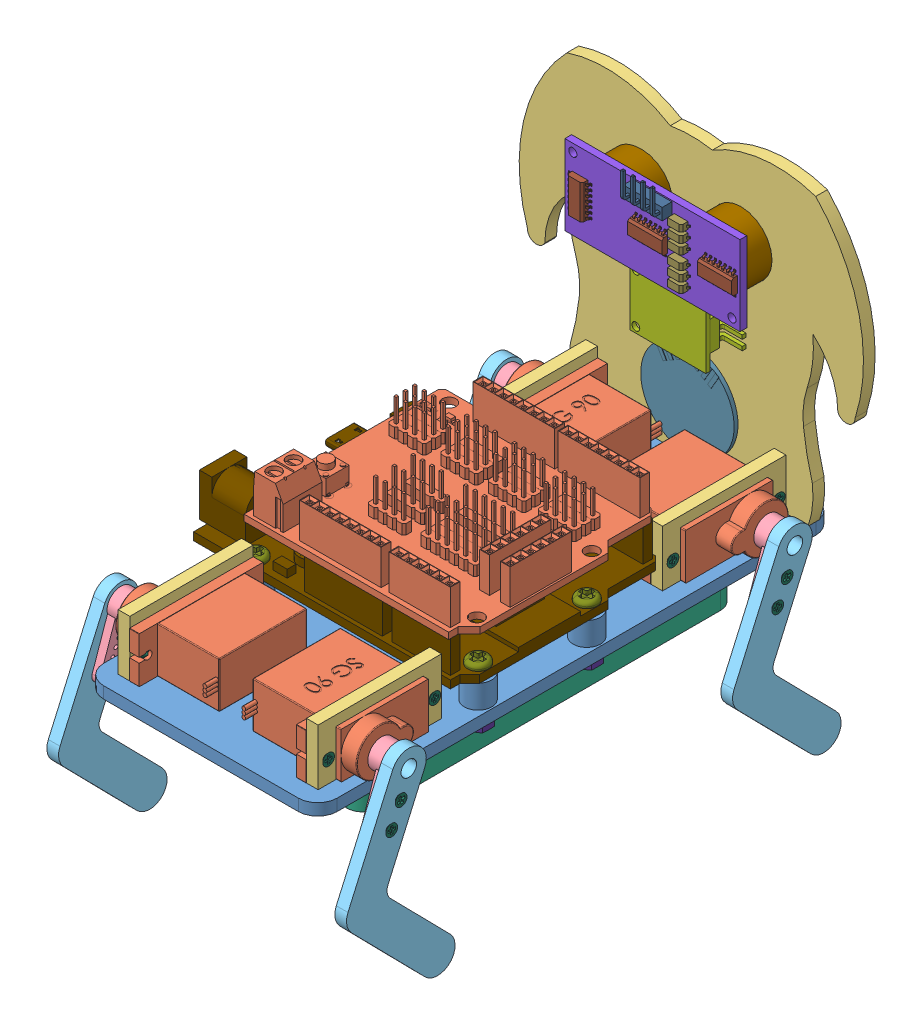
SolidWorks assembly nelo, configuration Default. Lengths in mm.
Overall size (88.48 121.83 157.12).
70 component instances, 21 part files, 115 mates.
Components (placement in the parent):
- Base-1: Base [Default] at (-3.0224 29.2064 91.2375) size (60 3 133)
- sg90-1: sg90 [Default] at (22.6776 44.0064 -3.7625) x (0 0 1) z (0 -1 0) size (31.9 29.9 11.8)
- sg90-2: sg90 [Default] at (31.2776 44.0064 107.2375) x (0 0 -1) z (0 -1 0) size (31.9 29.9 11.8)
- sg90-3: sg90 [Default] at (22.6776 32.2064 107.2375) x (0 0 -1) z (0 1 0) size (31.9 29.9 11.8)
- sg90-4: sg90 [Default] at (31.2776 32.2064 -3.7625) x (0 0 1) z (0 1 0) size (31.9 29.9 11.8)
- servo_support-1: servo_support [Default] at (52.6776 29.2064 80.1375) x (0 0 1) z (-1 0 0) size (31.7 17.4 3)
- servo_support-2: servo_support [Default] at (52.6776 29.2064 -8.3625) x (0 0 1) z (-1 0 0) size (31.7 17.4 3)
- servo_support-3: servo_support [Default] at (4.2776 29.2064 -8.3625) x (0 0 1) z (-1 0 0) size (31.7 17.4 3)
- servo_support-4: servo_support [Default] at (4.2776 29.2064 80.1375) x (0 0 1) z (-1 0 0) size (31.7 17.4 3)
- SG90 plastic Horn-1: SG90 plastic Horn [Default] at (-6.5224 38.1064 2.1375) x (0 -0.914668 0.404206) z (0 -0.404206 -0.914668) size (19.4 4 7.07)
- SG90 plastic Horn-2: SG90 plastic Horn [Default] at (-6.5224 38.1064 101.3375) x (0 -0.914668 0.404206) z (0 -0.404206 -0.914668) size (19.4 4 7.07)
- SG90 plastic Horn-3: SG90 plastic Horn [Default] at (60.4776 38.1064 2.1375) x (0 -0.914668 0.404206) z (0 0.404206 0.914668) size (19.4 4 7.07)
- SG90 plastic Horn-4: SG90 plastic Horn [Default] at (60.4776 38.1064 101.3375) x (0 -0.914668 0.404206) z (0 0.404206 0.914668) size (19.4 4 7.07)
- leg-1: leg [Default] at (-8.5224 11.4611 5.5657) x (0 0.713421 0.700736) z (0 -0.700736 0.713421) size (46.53 3 35.49)
- leg-2: leg [Default] at (-8.5224 11.4611 104.7657) x (0 0.713421 0.700736) z (0 -0.700736 0.713421) size (46.53 3 35.49)
- leg-3: leg [Default] at (65.4776 11.4611 5.5657) x (0 0.713421 0.700736) z (0 -0.700736 0.713421) size (46.53 3 35.49)
- leg-4: leg [Default] at (65.4776 11.4611 104.7657) x (0 0.713421 0.700736) z (0 -0.700736 0.713421) size (46.53 3 35.49)
- PowerBank-1: PowerBank [Default] at (27.4776 7.2064 39.2375) x (0 0 1) z (-1 0 0) size (96 22 24)
- BU-1: BU [Predeterminado] at (17.6146 61.9245 -3.7625) x (-1 0 0) z (0 0 -1) size (23.75 15.4 11)
- HC-SR04 Ping Sensor-1: HC-SR04 Ping Sensor [Default] at (26.7276 86.7315 -0.0125) x (0 1 0) z (0 0 -1) size (25.18 45 18.07)
  - PCB-1: PCB [Default] at origin size (20.5 45 1.75)
  - Transducer-1: Transducer [Default] at (0 -13 13.25) x (1 0 0) z (0 -1 0) size (15.88 12 15.88)
  - Transducer-2: Transducer [Default] at (0 13 13.25) x (1 0 0) z (0 -1 0) size (15.88 12 15.88)
  - 3 Pin Header 90 Degree-1: 3 Pin Header 90 Degree [Default] at (8.4275 0 -1.25) x (-1 0 0) z (0 -1 0) size (8 7.82 10)
  - 14 Pin SMT-1: 14 Pin SMT [Default] at (-0.35 -18.5 -0.85) x (0 -1 0) z (1 0 0) size (6 1.6 8.8)
  - 14 Pin SMT-2: 14 Pin SMT [Default] at (0 -0.3826 -0.85) x (1 0 0) z (0 1 0) size (6 1.6 8.8)
  - 14 Pin SMT-3: 14 Pin SMT [Default] at (0 17.5274 -0.85) x (1 0 0) z (0 1 0) size (6 1.6 8.8)
  - Cap1 SMT-1: Cap1 SMT [Default] at (-1.755 7.4774 -0.9689) x (0 1 0) z (-1 0 0) size (4.5 1.84 1.75)
  - Cap1 SMT-2: Cap1 SMT [Default] at (6.835 7.4774 -0.9689) x (0 1 0) z (-1 0 0) size (4.5 1.84 1.75)
  - Cap1 SMT-3: Cap1 SMT [Default] at (-6.835 7.4774 -0.9689) x (0 1 0) z (-1 0 0) size (4.5 1.84 1.75)
  - Cap1 SMT-4: Cap1 SMT [Default] at (4.295 7.4774 -0.9689) x (0 1 0) z (-1 0 0) size (4.5 1.84 1.75)
  - Cap1 SMT-5: Cap1 SMT [Default] at (1.755 7.4774 -0.9689) x (0 1 0) z (-1 0 0) size (4.5 1.84 1.75)
  - Cap1 SMT-6: Cap1 SMT [Default] at (-4.295 7.4774 -0.9689) x (0 1 0) z (-1 0 0) size (4.5 1.84 1.75)
  - HC-SR04 Crystal-1: HC-SR04 Crystal [Default] at (-8.3 0 1.75) x (0 -1 0) z (0 0 1) size (10 3.5 2.7)
- ws8212-7-1: ws8212-7 [Predeterminado] at (26.9776 45.8155 -8.7625) x (0 1 0) z (0 0 -1) size (24 24 3.1)
- M2x6 SelfTap Screw-1: M2x6 SelfTap Screw [Predeterminado] at (-8.2224 38.1064 2.1375) x (0 -0.924225 -0.381849) z (-1 0 0) size (3.4 3.28 6)
- M2x6 SelfTap Screw-2: M2x6 SelfTap Screw [Predeterminado] at (-8.2224 38.1064 101.3375) x (0 0.924225 0.381849) z (-1 0 0) size (3.4 3.28 6)
- M2x6 SelfTap Screw-3: M2x6 SelfTap Screw [Predeterminado] at (62.1776 38.1064 2.1375) x (0 -0.924225 -0.381849) z (1 0 0) size (3.4 3.28 6)
- M2x6 SelfTap Screw-4: M2x6 SelfTap Screw [Predeterminado] at (62.1776 38.1064 101.3375) x (0 -0.924225 -0.381849) z (1 0 0) size (3.4 3.28 6)
- M2x6 SelfTap Screw-5: M2x6 SelfTap Screw [Predeterminado] at (65.9776 27.0527 7.0224) x (0 0 -1) z (1 0 0) size (3.4 3.28 6)
- M2x6 SelfTap Screw-6: M2x6 SelfTap Screw [Predeterminado] at (65.9776 27.0527 106.2224) x (0 0 -1) z (1 0 0) size (3.4 3.28 6)
- M2x6 SelfTap Screw-7: M2x6 SelfTap Screw [Predeterminado] at (-12.0224 27.0527 7.0224) x (0 0.924225 0.381849) z (-1 0 0) size (3.4 3.28 6)
- M2x6 SelfTap Screw-8: M2x6 SelfTap Screw [Predeterminado] at (-12.0224 27.0527 106.2224) x (0 0 1) z (-1 0 0) size (3.4 3.28 6)
- M2x6 SelfTap Screw-9: M2x6 SelfTap Screw [Predeterminado] at (0.7776 38.1064 21.1375) x (0 0.924225 0.381849) z (-1 0 0) size (3.4 3.28 6)
- M2x6 SelfTap Screw-10: M2x6 SelfTap Screw [Predeterminado] at (0.7776 38.1064 -6.1625) x (0 0.924225 0.381849) z (-1 0 0) size (3.4 3.28 6)
- M2x6 SelfTap Screw-11: M2x6 SelfTap Screw [Predeterminado] at (0.7776 38.1064 82.3375) x (0 0.924225 0.381849) z (-1 0 0) size (3.4 3.28 6)
- M2x6 SelfTap Screw-12: M2x6 SelfTap Screw [Predeterminado] at (0.7776 38.1064 109.6375) x (0 0.924225 0.381849) z (-1 0 0) size (3.4 3.28 6)
- M2x6 SelfTap Screw-13: M2x6 SelfTap Screw [Predeterminado] at (53.1776 38.1064 109.6375) x (0 0 -1) z (1 0 0) size (3.4 3.28 6)
- M2x6 SelfTap Screw-14: M2x6 SelfTap Screw [Predeterminado] at (53.1776 38.1064 82.3375) x (0 0 -1) z (1 0 0) size (3.4 3.28 6)
- M2x6 SelfTap Screw-15: M2x6 SelfTap Screw [Predeterminado] at (53.1776 38.1064 -6.1625) x (0 0 -1) z (1 0 0) size (3.4 3.28 6)
- M2x6 SelfTap Screw-16: M2x6 SelfTap Screw [Predeterminado] at (53.1776 38.1064 21.1375) x (0 0 -1) z (1 0 0) size (3.4 3.28 6)
- M3x12 Philips Screw-1: M3x12 Philips Screw [Default] at (2.2476 39.8564 27.9287) x (1 0 0) z (0 1 0) size (5.3 5.3 13.8)
- M3x12 Philips Screw-2: M3x12 Philips Screw [Default] at (0.9776 39.8564 76.1887) x (1 0 0) z (0 1 0) size (5.3 5.3 13.8)
- M3x12 Philips Screw-3: M3x12 Philips Screw [Default] at (53.0476 39.8564 71.1087) x (1 0 0) z (0 1 0) size (5.3 5.3 13.8)
- M3x12 Philips Screw-4: M3x12 Philips Screw [Default] at (53.0476 39.8564 43.1687) x (1 0 0) z (0 1 0) size (5.3 5.3 13.8)
- M3 Nut-1: M3 Nut [Predeterminado] at (53.0476 30.7064 71.1087) x (1 0 0) z (0 1 0) size (6.27 6.27 2.71)
- M3 Nut-2: M3 Nut [Predeterminado] at (53.0476 30.7064 43.1687) x (1 0 0) z (0 1 0) size (6.27 6.27 2.71)
- M3 Nut-3: M3 Nut [Predeterminado] at (2.2476 25.2064 27.9287) x (1 0 0) z (0 -1 0) size (6.27 6.27 2.71)
- M3 Nut-4: M3 Nut [Predeterminado] at (0.9776 25.2064 76.1887) x (1 0 0) z (0 -1 0) size (6.27 6.27 2.71)
- wemosd1r32-1: wemosd1r32 [Predeterminado] at (21.4976 40.2064 51.4287) x (0 0 1) z (-1 0 0) size (54 14.5 70.5)
- separador-2: separador [Predeterminado] at (53.0476 38.2064 71.1087) x (1 0 0) z (0 -1 0) size (7 7 6)
- separador-1: separador [Predeterminado] at (2.2476 32.2064 27.9287) x (1 0 0) z (0 1 0) size (7 7 6)
- separador-3: separador [Predeterminado] at (0.9776 32.2064 76.1887) x (1 0 0) z (0 1 0) size (7 7 6)
- separador-4: separador [Predeterminado] at (53.0476 38.2064 43.1687) x (1 0 0) z (0 -1 0) size (7 7 6)
- Arduino Sensor Board V1-1: Arduino Sensor Board V1 [Predeterminado] at (26.7776 49.2064 51.8337) x (0 0 1) z (-1 0 0) size (53.65 20.91 58.16)
- M2x6 SelfTap Screw-18: M2x6 SelfTap Screw [Predeterminado] at (-12.0224 32.5407 4.5971) x (0 0 1) z (-1 0 0) size (3.4 3.28 6)
- M2x6 SelfTap Screw-19: M2x6 SelfTap Screw [Predeterminado] at (-12.0224 32.5407 103.7971) x (0 0.924225 0.381849) z (-1 0 0) size (3.4 3.28 6)
- M2x6 SelfTap Screw-20: M2x6 SelfTap Screw [Predeterminado] at (65.9776 32.5407 103.7971) x (0 -0.924225 -0.381849) z (1 0 0) size (3.4 3.28 6)
- M2x6 SelfTap Screw-21: M2x6 SelfTap Screw [Predeterminado] at (65.9776 32.5407 4.5971) x (0 -0.924225 -0.381849) z (1 0 0) size (3.4 3.28 6)
- dog_face-1: dog_face [Default] at (-14.2037 110.2385 -12.7625) x (0 -1 0) z (0 0 1) size (79.03 88.48 3)
Mates (geometry in assembly coordinates):
- Coincident1: coincident: plane of Base-1 through (51.9776 32.2064 111.2375) normal (0 1 0); plane of sg90-1 through (22.6776 32.2064 -3.7625) normal (0 -1 0)
- Distance1: distance = 3 mm: plane of sg90-1 through (-0.0224 32.2064 -3.7625) normal (-1 0 0); plane of Base-1 through (-3.0224 32.2064 111.2375) normal (-1 0 0)
- Coincident5: coincident: plane of Base-1 through (51.9776 32.2064 111.2375) normal (0 1 0); plane of sg90-2 through (31.2776 32.2064 107.2375) normal (0 -1 0)
- Coincident7: coincident: plane of Base-1 through (49.6776 32.2064 84.7375) normal (0 0 -1); plane of sg90-2 through (31.2776 32.2064 84.7375) normal (0 0 -1)
- Coincident8: coincident: plane of Base-1 through (49.6776 32.2064 107.2375) normal (1 0 0); plane of sg90-2 through (49.6776 44.0064 111.9375) normal (1 0 0)
- Coincident9: coincident: plane of Base-1 through (51.9776 32.2064 111.2375) normal (0 1 0); plane of sg90-3 through (22.6776 32.2064 107.2375) normal (0 -1 0)
- Coincident10: coincident: plane of sg90-1 through (-0.0224 32.2064 -3.7625) normal (-1 0 0); plane of sg90-3 through (-0.0224 44.0064 107.2375) normal (-1 0 0)
- Coincident11: coincident: plane of Base-1 through (4.2776 32.2064 107.2375) normal (0 0 1); plane of sg90-3 through (22.6776 44.0064 107.2375) normal (0 0 1)
- Coincident12: coincident: plane of Base-1 through (51.9776 32.2064 111.2375) normal (0 1 0); plane of sg90-4 through (31.2776 32.2064 -3.7625) normal (0 -1 0)
- Coincident13: coincident: plane of sg90-2 through (53.9776 32.2064 107.2375) normal (1 0 0); plane of sg90-4 through (53.9776 44.0064 -3.7625) normal (1 0 0)
- Coincident14: coincident: plane of Base-1 through (49.6776 32.2064 -3.7625) normal (0 0 -1); plane of sg90-4 through (31.2776 44.0064 -3.7625) normal (0 0 -1)
- Coincident15: coincident: plane of Base-1 through (49.6776 32.2064 107.2375) normal (1 0 0); plane of servo_support-1 through (49.6776 29.2064 80.1375) normal (-1 0 0)
- Coincident16: coincident: plane of Base-1 through (49.6776 32.2064 111.8375) normal (0 0 -1); plane of servo_support-1 through (49.6776 29.2064 111.8375) normal (0 0 1)
- Coincident17: coincident: plane of Base-1 through (51.9776 29.2064 111.2375) normal (0 -1 0); plane of servo_support-1 through (49.6776 29.2064 107.2375) normal (0 -1 0)
- Coincident18: coincident: plane of Base-1 through (49.6776 32.2064 18.7375) normal (1 0 0); plane of servo_support-2 through (49.6776 29.2064 -8.3625) normal (-1 0 0)
- Coincident20: coincident: plane of Base-1 through (49.6776 32.2064 18.7375) normal (0 0 1); plane of servo_support-2 through (49.6776 43.6064 18.7375) normal (0 0 -1)
- Coincident21: coincident: plane of Base-1 through (51.9776 29.2064 111.2375) normal (0 -1 0); plane of servo_support-2 through (49.6776 29.2064 18.7375) normal (0 -1 0)
- Coincident22: coincident: plane of Base-1 through (4.2776 32.2064 -3.7625) normal (-1 0 0); plane of servo_support-3 through (4.2776 29.2064 -8.3625) normal (1 0 0)
- Coincident23: coincident: plane of Base-1 through (4.2776 32.2064 -8.3625) normal (0 0 1); plane of servo_support-3 through (1.2776 46.6064 -8.3625) normal (0 0 -1)
- Coincident24: coincident: plane of Base-1 through (51.9776 29.2064 111.2375) normal (0 -1 0); plane of servo_support-3 through (1.2776 29.2064 -8.3625) normal (0 -1 0)
- Coincident25: coincident: plane of Base-1 through (4.2776 32.2064 84.7375) normal (-1 0 0); plane of servo_support-4 through (4.2776 29.2064 80.1375) normal (1 0 0)
- Coincident26: coincident: plane of Base-1 through (51.9776 29.2064 111.2375) normal (0 -1 0); plane of servo_support-4 through (1.2776 29.2064 80.1375) normal (0 -1 0)
- Coincident27: coincident: plane of Base-1 through (4.2776 32.2064 80.1375) normal (0 0 1); plane of servo_support-4 through (1.2776 46.6064 80.1375) normal (0 0 -1)
- Concentric1: concentric: circle of sg90-1; circle of SG90 plastic Horn-1
- Distance4: distance = 0.5 mm: plane of SG90 plastic Horn-1 through (-4.5224 35.9341 3.0975) normal (1 0 0); plane of sg90-1 through (-4.0224 38.1064 2.1375) normal (-1 0 0)
- Concentric2: concentric: circle of sg90-3; circle of SG90 plastic Horn-2
- Distance5: distance = 0.5 mm: plane of SG90 plastic Horn-2 through (-4.5224 35.9341 102.2975) normal (1 0 0); plane of sg90-3 through (-4.0224 38.1064 101.3375) normal (-1 0 0)
- Concentric3: concentric: circle of sg90-4; circle of SG90 plastic Horn-3
- Distance6: distance = 0.5 mm: plane of sg90-4 through (57.9776 38.1064 2.1375) normal (1 0 0); plane of SG90 plastic Horn-3 through (58.4776 35.9341 3.0975) normal (-1 0 0)
- Concentric4: concentric: circle of sg90-2; circle of SG90 plastic Horn-4
- Distance7: distance = 0.5 mm: plane of SG90 plastic Horn-4 through (58.4776 35.9341 102.2975) normal (-1 0 0); plane of sg90-2 through (57.9776 38.1064 101.3375) normal (1 0 0)
- Concentric5: concentric: circle of SG90 plastic Horn-1; circle of leg-1
- Coincident32: coincident: plane of SG90 plastic Horn-1 through (-8.5224 34.8731 3.5664) normal (-1 0 0); plane of leg-1 through (-8.5224 38.1064 2.1375) normal (1 0 0)
- Concentric7: concentric: circle of SG90 plastic Horn-1; circle of leg-1
- Concentric8: concentric: circle of SG90 plastic Horn-2; circle of leg-2
- Coincident35: coincident: plane of SG90 plastic Horn-2 through (-8.5224 34.8731 102.7664) normal (-1 0 0); plane of leg-2 through (-8.5224 38.1064 101.3375) normal (1 0 0)
- Concentric9: concentric: circle of SG90 plastic Horn-2; circle of leg-2
- Concentric10: concentric: circle of SG90 plastic Horn-3; circle of leg-3
- Coincident37: coincident: plane of SG90 plastic Horn-3 through (62.4776 34.8731 3.5664) normal (1 0 0); plane of leg-3 through (62.4776 38.1064 2.1375) normal (-1 0 0)
- Concentric11: concentric: circle of SG90 plastic Horn-3; circle of leg-3
- Concentric12: concentric: circle of SG90 plastic Horn-4; circle of leg-4
- Coincident39: coincident: plane of SG90 plastic Horn-4 through (62.4776 34.8731 102.7664) normal (1 0 0); plane of leg-4 through (62.4776 38.1064 101.3375) normal (-1 0 0)
- Concentric13: concentric: circle of SG90 plastic Horn-4; circle of leg-4
- Coincident40: coincident: plane of Base-1 through (51.9776 29.2064 111.2375) normal (0 -1 0); plane of PowerBank-1 through (19.4776 29.2064 -4.7625) normal (0 1 0)
- Distance9: distance = 17.5 mm: plane of PowerBank-1 through (39.4776 29.2064 -4.7625) normal (1 0 0); plane of Base-1 through (56.9776 32.2064 111.2375) normal (1 0 0)
- Coincident56: coincident: plane of sg90-1 through (22.6776 32.2064 -3.7625) normal (0 0 -1); plane of servo_support-3 through (1.2776 29.2064 -3.7625) normal (0 0 1)
- Parallel6: parallel: plane of Base-1 through (51.9776 32.2064 111.2375) normal (0 1 0); plane of BU-1 through (17.6146 74.4315 -4.7625) normal (0 1 0)
- Parallel7: parallel: plane of Base-1 through (51.9776 32.2064 111.2375) normal (0 1 0); plane of HC-SR04 Ping Sensor-1/PCB-1 through (49.2276 96.9815 -1.7625) normal (0 1 0)
- Parallel10: parallel: plane of leg-1 through (-11.5224 -10.3773 -2.0521) normal (0 -0.700736 0.713421); plane of leg-2 through (-11.5224 -10.3773 97.1479) normal (0 -0.700736 0.713421)
- Parallel11: parallel: plane of leg-3 through (62.4776 -10.3773 -2.0521) normal (0 -0.700736 0.713421); plane of leg-4 through (62.4776 -10.3773 97.1479) normal (0 -0.700736 0.713421)
- Concentric25: concentric: circle of leg-1; circle of M2x6 SelfTap Screw-1
- Distance13: distance = 0.5 mm: plane of M2x6 SelfTap Screw-1 through (-8.2224 38.1064 2.1375) normal (-1 0 0); plane of SG90 plastic Horn-1 through (-7.7224 35.8426 3.1379) normal (-1 0 0)
- Concentric26: concentric: circle of SG90 plastic Horn-2; circle of M2x6 SelfTap Screw-2
- Distance14: distance = 0.5 mm: plane of M2x6 SelfTap Screw-2 through (-8.2224 38.1064 101.3375) normal (-1 0 0); plane of SG90 plastic Horn-2 through (-7.7224 35.8426 102.3379) normal (-1 0 0)
- Concentric27: concentric: circle of SG90 plastic Horn-3; circle of M2x6 SelfTap Screw-3
- Distance15: distance = 0.5 mm: plane of M2x6 SelfTap Screw-3 through (62.1776 38.1064 2.1375) normal (1 0 0); plane of SG90 plastic Horn-3 through (61.6776 35.8426 3.1379) normal (1 0 0)
- Concentric28: concentric: circle of SG90 plastic Horn-4; circle of M2x6 SelfTap Screw-4
- Distance16: distance = 0.5 mm: plane of M2x6 SelfTap Screw-4 through (62.1776 38.1064 101.3375) normal (1 0 0); plane of SG90 plastic Horn-4 through (61.6776 35.8426 102.3379) normal (1 0 0)
- Concentric29: concentric: circle of leg-3; circle of M2x6 SelfTap Screw-5
- Distance17: distance = 0.5 mm: plane of M2x6 SelfTap Screw-5 through (65.9776 27.0527 7.0224) normal (1 0 0); plane of leg-3 through (65.4776 38.1064 2.1375) normal (1 0 0)
- Concentric30: concentric: circle of leg-4; circle of M2x6 SelfTap Screw-6
- Distance18: distance = 0.5 mm: plane of M2x6 SelfTap Screw-6 through (65.9776 27.0527 106.2224) normal (1 0 0); plane of leg-4 through (65.4776 38.1064 101.3375) normal (1 0 0)
- Concentric31: concentric: circle of leg-1; circle of M2x6 SelfTap Screw-7
- Distance19: distance = 0.5 mm: plane of M2x6 SelfTap Screw-7 through (-12.0224 27.0527 7.0224) normal (-1 0 0); plane of leg-1 through (-11.5224 38.1064 2.1375) normal (-1 0 0)
- Distance20: distance = 0.5 mm: plane of M2x6 SelfTap Screw-8 through (-12.0224 27.0527 106.2224) normal (-1 0 0); plane of leg-2 through (-11.5224 38.1064 101.3375) normal (-1 0 0)
- Concentric32: concentric: circle of leg-2; circle of M2x6 SelfTap Screw-8
- Concentric33: concentric: circle of servo_support-3; circle of M2x6 SelfTap Screw-9
- Distance21: distance = 0.5 mm: plane of M2x6 SelfTap Screw-9 through (0.7776 38.1064 21.1375) normal (-1 0 0); plane of servo_support-3 through (1.2776 29.2064 -8.3625) normal (-1 0 0)
- Concentric34: concentric: circle of servo_support-3; circle of M2x6 SelfTap Screw-10
- Distance22: distance = 0.5 mm: plane of M2x6 SelfTap Screw-10 through (0.7776 38.1064 -6.1625) normal (-1 0 0); plane of servo_support-3 through (1.2776 29.2064 -8.3625) normal (-1 0 0)
- Concentric35: concentric: circle of servo_support-4; circle of M2x6 SelfTap Screw-11
- Distance23: distance = 0.5 mm: plane of M2x6 SelfTap Screw-11 through (0.7776 38.1064 82.3375) normal (-1 0 0); plane of servo_support-4 through (1.2776 29.2064 80.1375) normal (-1 0 0)
- Concentric36: concentric: circle of servo_support-4; circle of M2x6 SelfTap Screw-12
- Distance24: distance = 0.5 mm: plane of M2x6 SelfTap Screw-12 through (0.7776 38.1064 109.6375) normal (-1 0 0); plane of servo_support-4 through (1.2776 29.2064 80.1375) normal (-1 0 0)
- Concentric37: concentric: circle of servo_support-1; circle of M2x6 SelfTap Screw-13
- Distance25: distance = 0.5 mm: plane of M2x6 SelfTap Screw-13 through (53.1776 38.1064 109.6375) normal (1 0 0); plane of servo_support-1 through (52.6776 29.2064 80.1375) normal (1 0 0)
- Concentric38: concentric: circle of servo_support-1; circle of M2x6 SelfTap Screw-14
- Distance27: distance = 0.5 mm: plane of servo_support-1 through (52.6776 29.2064 80.1375) normal (1 0 0); plane of M2x6 SelfTap Screw-14 through (53.1776 38.1064 82.3375) normal (1 0 0)
- Concentric39: concentric: circle of servo_support-2; circle of M2x6 SelfTap Screw-15
- Distance28: distance = 0.5 mm: plane of M2x6 SelfTap Screw-15 through (53.1776 38.1064 -6.1625) normal (1 0 0); plane of servo_support-2 through (52.6776 29.2064 -8.3625) normal (1 0 0)
- Concentric40: concentric: circle of servo_support-2; circle of M2x6 SelfTap Screw-16
- Distance29: distance = 0.5 mm: plane of servo_support-2 through (52.6776 29.2064 -8.3625) normal (1 0 0); plane of M2x6 SelfTap Screw-16 through (53.1776 38.1064 21.1375) normal (1 0 0)
- Coincident105: coincident: plane of Base-1 through (51.9776 29.2064 111.2375) normal (0 -1 0); plane of M3 Nut-1 through (53.0476 29.2064 71.1087) normal (0 1 0)
- Concentric46: concentric: circle of M3x12 Philips Screw-3; circle of M3 Nut-1
- Coincident106: coincident: plane of Base-1 through (51.9776 29.2064 111.2375) normal (0 -1 0); plane of M3 Nut-2 through (53.0476 29.2064 43.1687) normal (0 1 0)
- Concentric47: concentric: circle of M3x12 Philips Screw-4; circle of M3 Nut-2
- Coincident107: coincident: plane of Base-1 through (51.9776 29.2064 111.2375) normal (0 -1 0); plane of M3 Nut-3 through (2.2476 29.2064 27.9287) normal (0 1 0)
- Concentric48: concentric: circle of M3x12 Philips Screw-1; circle of M3 Nut-3
- Coincident108: coincident: plane of Base-1 through (51.9776 29.2064 111.2375) normal (0 -1 0); plane of M3 Nut-4 through (0.9776 29.2064 76.1887) normal (0 1 0)
- Concentric49: concentric: circle of M3x12 Philips Screw-2; circle of M3 Nut-4
- Coincident112: coincident: plane of Base-1 through (51.9776 32.2064 111.2375) normal (0 1 0); plane of separador-1 through (2.2476 32.2064 27.9287) normal (0 -1 0)
- Concentric54: concentric: circle of Base-1; circle of separador-1
- Coincident113: coincident: plane of wemosd1r32-1 through (21.4976 38.2064 51.4287) normal (0 -1 0); plane of separador-1 through (2.2476 38.2064 27.9287) normal (0 1 0)
- Coincident114: coincident: plane of Base-1 through (51.9776 32.2064 111.2375) normal (0 1 0); plane of separador-2 through (53.0476 32.2064 71.1087) normal (0 -1 0)
- Concentric55: concentric: circle of Base-1; circle of separador-2
- Concentric56: concentric: circle of wemosd1r32-1; circle of separador-1
- Parallel12: parallel: plane of Base-1 through (56.9776 32.2064 111.2375) normal (1 0 0); plane of wemosd1r32-1 through (55.7476 40.2064 63.4287) normal (1 0 0)
- Coincident116: coincident: plane of Base-1 through (51.9776 32.2064 111.2375) normal (0 1 0); plane of separador-3 through (0.9776 32.2064 76.1887) normal (0 -1 0)
- Concentric59: concentric: circle of Base-1; circle of separador-3
- Coincident117: coincident: plane of Base-1 through (51.9776 32.2064 111.2375) normal (0 1 0); plane of separador-4 through (53.0476 32.2064 43.1687) normal (0 -1 0)
- Concentric60: concentric: circle of Base-1; circle of separador-4
- Coincident120: coincident: plane of wemosd1r32-1 through (49.7476 40.2064 77.4287) normal (0 0 1); plane of Arduino Sensor Board V1-1 through (36.4476 50.8564 77.4287) normal (0 0 1)
- Coincident121: coincident: plane of wemosd1r32-1 through (52.2476 40.2064 77.4287) normal (1 0 0); plane of Arduino Sensor Board V1-1 through (52.2476 50.8564 77.4287) normal (1 0 0)
- Coincident122: coincident: plane of wemosd1r32-1 through (21.4976 49.2064 51.4287) normal (0 1 0); plane of Arduino Sensor Board V1-1 through (26.4021 49.2064 51.8381) normal (0 -1 0)
- Distance30: distance = 0.5 mm: plane of M2x6 SelfTap Screw-18 through (-12.0224 32.5407 4.5971) normal (-1 0 0); plane of leg-1 through (-11.5224 38.1064 2.1375) normal (-1 0 0)
- Concentric62: concentric: circle of leg-1; circle of M2x6 SelfTap Screw-18
- Distance31: distance = 0.5 mm: plane of leg-2 through (-11.5224 38.1064 101.3375) normal (-1 0 0); plane of M2x6 SelfTap Screw-19 through (-12.0224 32.5407 103.7971) normal (-1 0 0)
- Concentric63: concentric: circle of leg-2; circle of M2x6 SelfTap Screw-19
- Distance32: distance = 0.5 mm: plane of leg-4 through (65.4776 38.1064 101.3375) normal (1 0 0); plane of M2x6 SelfTap Screw-20 through (65.9776 32.5407 103.7971) normal (1 0 0)
- Concentric64: concentric: circle of leg-4; circle of M2x6 SelfTap Screw-20
- Distance33: distance = 0.5 mm: plane of leg-3 through (65.4776 38.1064 2.1375) normal (1 0 0); plane of M2x6 SelfTap Screw-21 through (65.9776 32.5407 4.5971) normal (1 0 0)
- Concentric65: concentric: circle of leg-3; circle of M2x6 SelfTap Screw-21
- Coincident127: coincident: plane of Base-1 through (51.9776 29.2064 111.2375) normal (0 -1 0); plane of dog_face-1 through (35.9776 29.2064 -9.7625) normal (0 -1 0)
- Coincident128: coincident: plane of Base-1 through (7.9776 32.2064 -12.7625) normal (0 0 1); plane of dog_face-1 through (66.7675 62.3722 -12.7625) normal (0 0 -1)
- Coincident129: coincident: plane of Base-1 through (7.9776 32.2064 -9.7625) normal (1 0 0); plane of dog_face-1 through (7.9776 32.2064 -9.7625) normal (-1 0 0)
